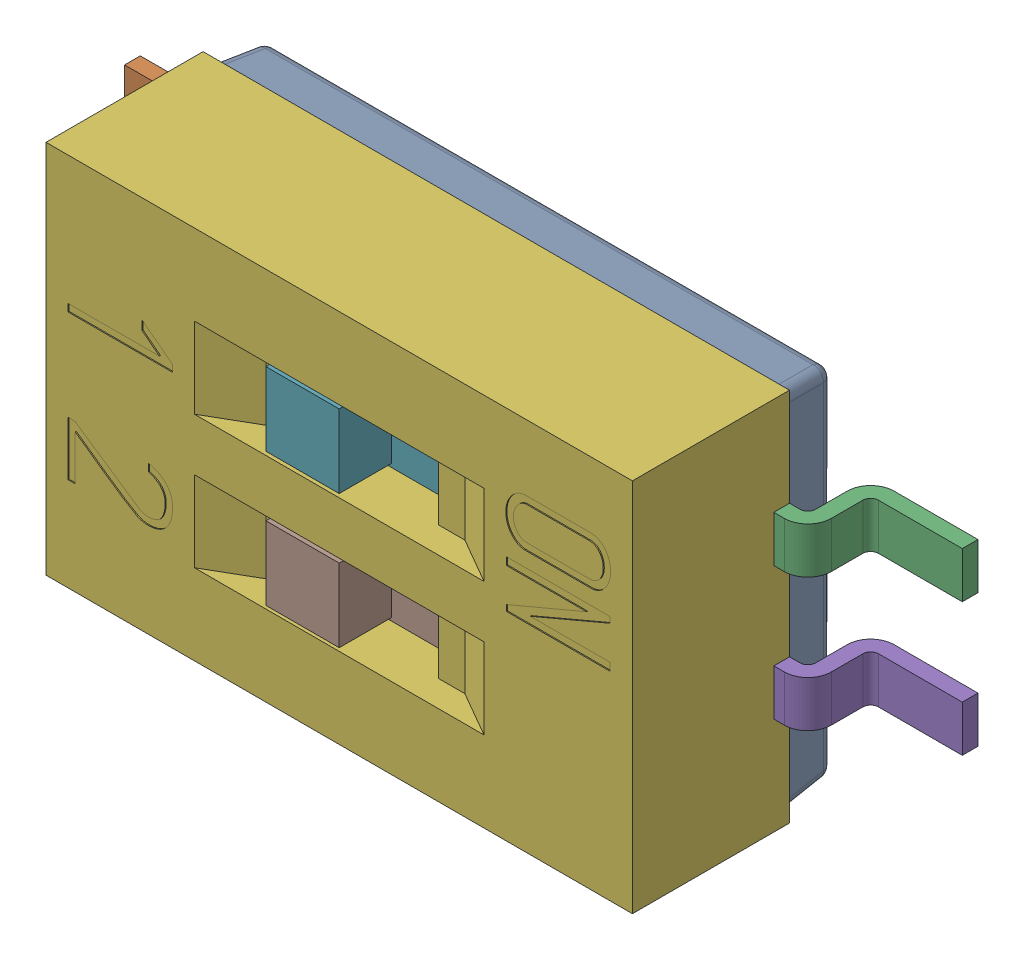
SolidWorks assembly SW200PCB, configuration Default. Lengths in mm.
Overall size (8 3.58 2.1).
9 component instances, 5 part files, 0 mates.
Components (placement in the parent):
- 416131160802-1: 416131160802 [Default] at (87.7001 117.5999 0.56) x (0 -1 0) z (0 0 1) size (3.58 8 2.1)
  - base_2-1: base_2 [Default] at origin size (3.48 5.5 0.65)
  - pins-1: pins [Default] at (-0.635 0 0) size (1 3.75 0.75)
  - pins_2-1: pins_2 [Default] at (-0.635 0 0) size (1 2.85 0.75)
  - pins-2: pins [Default] at (0.635 0 0) size (1 3.75 0.75)
  - pins_2-2: pins_2 [Default] at (0.635 0 0) size (1 2.85 0.75)
  - cap-1: cap [Default] at origin size (3.58 5.6 1.5)
  - clip-1: clip [Default] at (-0.635 0 0) size (1 2.6 0.95)
  - clip-2: clip [Default] at (0.64 0 0) size (1 2.6 0.95)
